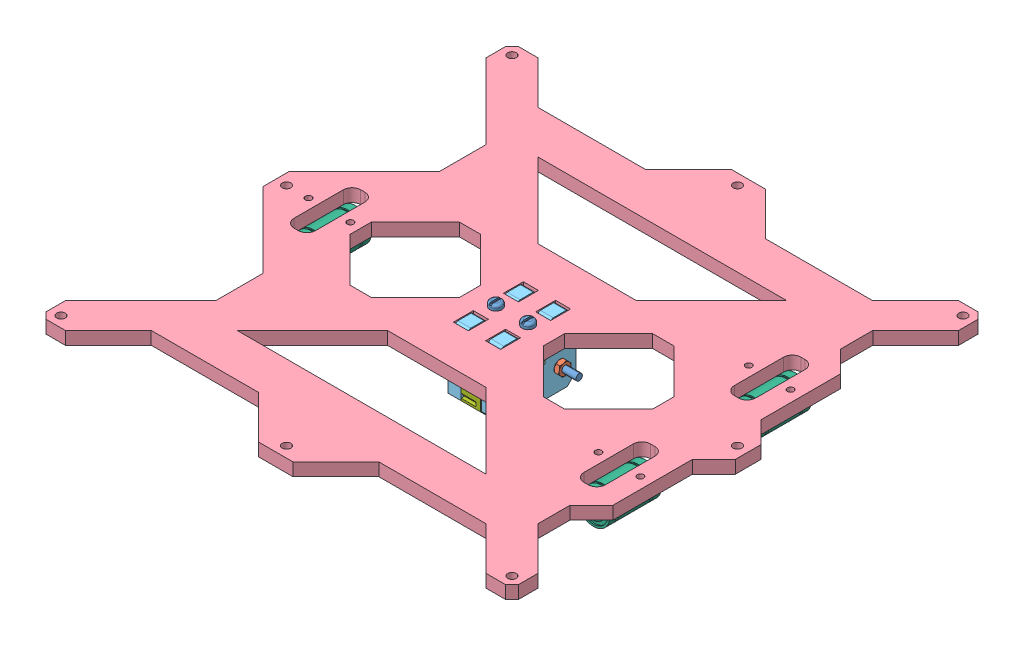
SolidWorks assembly frame_bed, configuration Défaut. Lengths in mm.
Overall size (220 33.48 220).
19 component instances, 7 part files, 41 mates.
Components (placement in the parent):
- pan slot head_am (threaded)-3: pan slot head_am (threaded) [B18.6.7M - M3 x 0.5 x 30 Slotted PHMS --30N] at (-12.9 -15 -11.8) size (32.48 5.6 5.6)
- pan slot head_am (threaded)-4: pan slot head_am (threaded) [B18.6.7M - M3 x 0.5 x 30 Slotted PHMS --30N] at (-12.9 -15 12.2) x (1 0 0) z (0 -0.254698 0.967021) size (32.48 5.6 5.6)
- hex nut style 1_am-1: hex nut style 1_am [B18.2.4.1M - Hex nut, Style 1,  M3 x 0.5 --D-N] at (10.5 -15 12.2) x (0 0.263857 0.964562) z (-1 0 0) size (5.5 6.35 2.4)
- hex nut style 1_am-2: hex nut style 1_am [B18.2.4.1M - Hex nut, Style 1,  M3 x 0.5 --D-N] at (10.5 -15 -11.8) x (0 0.263857 0.964562) z (-1 0 0) size (5.5 6.35 2.4)
- nut_fastener-1: nut_fastener [Défaut] at (-7.5 -5 0) x (0 0 1) z (1 0 0) size (8.2 22.48 7.7)
  - nut-1: nut [Défaut] at origin size (8.2 4.8 7.7)
  - pan slot head_am (threaded)-1: pan slot head_am (threaded) [B18.6.7M - M3 x 0.5 x 20 Slotted PHMS --20N] at (0 -13.4 0) x (0 1 0) z (-1 0 0) size (22.48 5.6 5.6)
  - hex nut style 1_am-2: hex nut style 1_am [B18.2.4.1M - Hex nut, Style 1,  M3 x 0.5 --D-N] at (0 4.6 0) x (0 0 1) z (0 1 0) size (5.5 6.35 2.4)
- nut_fastener-2: nut_fastener [Défaut] at (7.5 -5 0) x (0 0 1) z (1 0 0) size (8.2 22.48 7.7)
  - nut-1: nut [Défaut] at origin size (8.2 4.8 7.7)
  - pan slot head_am (threaded)-1: pan slot head_am (threaded) [B18.6.7M - M3 x 0.5 x 20 Slotted PHMS --20N] at (0 -13.4 0) x (0 1 0) z (-1 0 0) size (22.48 5.6 5.6)
  - hex nut style 1_am-2: hex nut style 1_am [B18.2.4.1M - Hex nut, Style 1,  M3 x 0.5 --D-N] at (0 4.6 0) x (0 0 1) z (0 1 0) size (5.5 6.35 2.4)
- frame_plate-1: frame_plate [Défaut] at origin size (220 6 220)
- frame_plate_carriage-1: frame_plate_carriage [Défaut] at (-10.5 -12.5 0.2) x (0 0 -1) z (1 0 0) size (38 31 6)
- frame_plate_carriage-2: frame_plate_carriage [Défaut] at (4.5 -12.5 -0.2) x (0 0 -1) z (1 0 0) size (38 31 6)
- bearing_lm8uu-1: bearing_lm8uu [Défaut] at (-85 -5.5902 12) x (0 -1 0) z (1 0 0) size (15 24 15)
- bearing_lm8uu-2: bearing_lm8uu [Défaut] at (85 -5.5902 -23) x (0 1 0) z (-1 0 0) size (15 24 15)
- bearing_lm8uu-3: bearing_lm8uu [Défaut] at (85 -5.5902 47) x (-1 0 0) z (0 -1 0) size (15 24 15)
- y_carriage-1: y_carriage [Défaut] at (4.5 -12.5 -9.3) x (0 0 1) z (-1 0 0) size (38 25 9)
Mates (geometry in assembly coordinates):
- Coaxiale1: concentric aligned: cylinder of frame_plate-1 through (-7.5 0 0) axis (0 1 0) radius 1.8; cylinder of nut_fastener-1/pan slot head_am (threaded)-1 through (-7.5 33.8 0) axis (0 1 0) radius 1.5
- Coaxiale2: concentric aligned: cylinder of frame_plate-1 through (7.5 0 0) axis (0 1 0) radius 1.8; cylinder of nut_fastener-2/pan slot head_am (threaded)-1 through (7.5 33.8 0) axis (0 1 0) radius 1.5
- Coïncidente4: coincident aligned: plane of frame_plate-1 through (0 6 0) normal (0 1 0); circle of nut_fastener-1/pan slot head_am (threaded)-1
- Parallèle7: parallel anti-aligned: line of frame_plate-1 through (100 6 -16) axis (0 0 -1); cylinder of bearing_lm8uu-2 through (85 -5.5902 -35) axis (0 0 1) radius 7.5
- Parallèle8: parallel anti-aligned: line of frame_plate-1 through (100 6 -16) axis (0 0 -1); cylinder of bearing_lm8uu-1 through (-85 -5.5902 0) axis (0 0 1) radius 7.5
- Parallèle9: parallel anti-aligned: line of frame_plate-1 through (100 6 -16) axis (0 0 -1); cylinder of bearing_lm8uu-3 through (85 -5.5902 35) axis (0 0 1) radius 7.5
- Tangent10: tangent: line of frame_plate-1 through (-90 0 -11.5) axis (0 0 1); cylinder of bearing_lm8uu-1 through (-85 -5.5902 0) axis (0 0 1) radius 7.5
- Tangent11: tangent: line of frame_plate-1 through (-80 0 11.5) axis (0 0 -1); cylinder of bearing_lm8uu-1 through (-85 -5.5902 0) axis (0 0 1) radius 7.5
- Tangent12: tangent: line of frame_plate-1 through (90 0 -23.5) axis (0 0 -1); cylinder of bearing_lm8uu-2 through (85 -5.5902 -35) axis (0 0 1) radius 7.5
- Tangent13: tangent: line of frame_plate-1 through (80 0 -46.5) axis (0 0 1); cylinder of bearing_lm8uu-2 through (85 -5.5902 -35) axis (0 0 1) radius 7.5
- Tangent14: tangent: line of frame_plate-1 through (80 0 23.5) axis (0 0 1); cylinder of bearing_lm8uu-3 through (85 -5.5902 35) axis (0 0 1) radius 7.5
- Tangent15: tangent: line of frame_plate-1 through (90 0 46.5) axis (0 0 -1); cylinder of bearing_lm8uu-3 through (85 -5.5902 35) axis (0 0 1) radius 7.5
- Parallèle12: parallel anti-aligned: plane of hex nut style 1_am-1 through (12.9 -14.1942 9.1285) normal (0 -0.263857 -0.964562); plane of hex nut style 1_am-2 through (12.9 -12.7429 -9.5664) normal (0 0.263857 0.964562)
- Coïncidente14: coordinate: point of frame_plate-1; point of assembly
- Coïncidente16: coincident anti-aligned: plane of frame_plate-1 through (0 0 0) normal (0 -1 0); plane of frame_plate_carriage-1 through (-4.5 0 19.2) normal (0 1 0)
- Coïncidente17: coincident aligned: plane of frame_plate_carriage-1 through (-10.5 6 0.2) normal (0 1 0); plane of frame_plate_carriage-2 through (4.5 6 -0.2) normal (0 1 0)
- Coaxiale3: concentric aligned: cylinder of frame_plate-1 through (7.5 0 0) axis (0 1 0) radius 1.8; cylinder of nut_fastener-2/pan slot head_am (threaded)-1 through (7.5 33.8 0) axis (0 1 0) radius 1.5
- Coïncidente18: coincident anti-aligned: plane of frame_plate-1 through (0 6 0) normal (0 1 0); plane of nut_fastener-2/pan slot head_am (threaded)-1 through (6 6 0) normal (0 -1 0)
- Coïncidente19: coincident anti-aligned: plane of frame_plate_carriage-1 through (-10.5 -12.5 -4.1) normal (0 0 1); plane of nut_fastener-1/nut-1 through (-7.5 -9.8 -4.1) normal (0 0 -1)
- Coïncidente20: coincident anti-aligned: plane of frame_plate_carriage-2 through (4.5 -12.5 4.1) normal (0 0 -1); plane of nut_fastener-2/nut-1 through (7.5 -9.8 4.1) normal (0 0 1)
- Perpendiculaire2: perpendicular: plane of frame_plate_carriage-1 through (-10.5 -12.5 0.2) normal (-1 0 0); plane of assembly through (0 0 0) normal (0 0 1)
- Perpendiculaire3: perpendicular: plane of frame_plate_carriage-2 through (4.5 -12.5 -0.2) normal (-1 0 0); plane of assembly through (0 0 0) normal (0 0 1)
- Coïncidente24: coincident anti-aligned: plane of frame_plate_carriage-2 through (4.5 -12.5 -0.2) normal (-1 0 0); plane of y_carriage-1 through (4.5 -12.5 -9.3) normal (1 0 0)
- Coïncidente25: coincident anti-aligned: plane of frame_plate_carriage-1 through (-4.5 -12.5 0.2) normal (1 0 0); plane of y_carriage-1 through (-4.5 -12.5 -9.3) normal (-1 0 0)
- Coïncidente26: coincident aligned: plane of frame_plate_carriage-2 through (10.5 -25 18.8) normal (0 -1 0); plane of y_carriage-1 through (-4.5 -25 -18.8) normal (0 -1 0)
- Coïncidente27: coincident aligned: plane of frame_plate_carriage-1 through (-4.5 0 19.2) normal (0 0 1); plane of y_carriage-1 through (-4.5 0 19.2) normal (0 0 1)
- Coaxiale4: concentric anti-aligned: cylinder of frame_plate_carriage-1 through (-10.5 -15 12.2) axis (1 0 0) radius 2.0524; cylinder of pan slot head_am (threaded)-4 through (-38.3 -15 12.2) axis (-1 0 0) radius 1.5
- Coaxiale5: concentric anti-aligned: cylinder of frame_plate_carriage-1 through (-10.5 -15 -11.8) axis (1 0 0) radius 2.0524; cylinder of pan slot head_am (threaded)-3 through (-38.3 -15 -11.8) axis (-1 0 0) radius 1.5
- Coïncidente28: coincident anti-aligned: plane of frame_plate_carriage-1 through (-10.5 -12.5 0.2) normal (-1 0 0); plane of pan slot head_am (threaded)-4 through (-10.5 -13.5495 12.582) normal (1 0 0)
- Coïncidente29: coincident anti-aligned: plane of frame_plate_carriage-1 through (-10.5 -12.5 0.2) normal (-1 0 0); plane of pan slot head_am (threaded)-3 through (-10.5 -13.5 -11.8) normal (1 0 0)
- Coaxiale6: concentric aligned: cylinder of pan slot head_am (threaded)-4 through (-38.3 -15 12.2) axis (-1 0 0) radius 1.5; circle of hex nut style 1_am-1
- Coaxiale7: concentric aligned: cylinder of pan slot head_am (threaded)-3 through (-38.3 -15 -11.8) axis (-1 0 0) radius 1.5; cylinder of hex nut style 1_am-2 through (12.9 -15 -11.8) axis (-1 0 0) radius 1.25
- Coïncidente30: coincident anti-aligned: plane of frame_plate_carriage-2 through (10.5 -12.5 -0.2) normal (1 0 0); plane of hex nut style 1_am-1 through (10.5 -11.9371 11.3621) normal (-1 0 0)
- Coïncidente31: coincident anti-aligned: plane of frame_plate_carriage-2 through (10.5 -12.5 -0.2) normal (1 0 0); plane of hex nut style 1_am-2 through (10.5 -11.9371 -12.6379) normal (-1 0 0)
- Distance3: distance = 10.5 mm: point of assembly; line of frame_plate_carriage-1 through (-10.5 0 2.7) axis (0 0 1)
- Largeur1: width anti-aligned: plane of frame_plate-1 through (84 -4 50.5) normal (0 0 -1); plane of frame_plate-1 through (84 -4 19.5) normal (0 0 1); plane of bearing_lm8uu-3 through (85 -5.5902 47) normal (0 0 1); plane of bearing_lm8uu-3 through (85 -5.5902 23) normal (0 0 -1)
- Parallèle20: parallel anti-aligned: plane of bearing_lm8uu-3 through (85 -5.5902 47) normal (0 -1 0); plane of assembly through (0 0 0) normal (0 1 0)
- Parallèle21: parallel aligned: plane of bearing_lm8uu-2; plane of assembly through (0 0 0) normal (0 1 0)
- Largeur2: width aligned: plane of frame_plate-1 through (84 -4 -19.5) normal (0 0 -1); plane of frame_plate-1 through (84 -4 -50.5) normal (0 0 1); plane of bearing_lm8uu-2 through (85 -5.5902 -47) normal (0 0 -1); plane of bearing_lm8uu-2 through (85 -5.5902 -23) normal (0 0 1)
- Parallèle22: parallel anti-aligned: plane of bearing_lm8uu-1; plane of assembly through (0 0 0) normal (0 1 0)
- Largeur3: width aligned: plane of frame_plate-1 through (-86 -4 -15.5) normal (0 0 1); plane of frame_plate-1 through (-86 -4 15.5) normal (0 0 -1); plane of bearing_lm8uu-1 through (-85 -5.5902 12) normal (0 0 1); plane of bearing_lm8uu-1 through (-85 -5.5902 -12) normal (0 0 -1)
